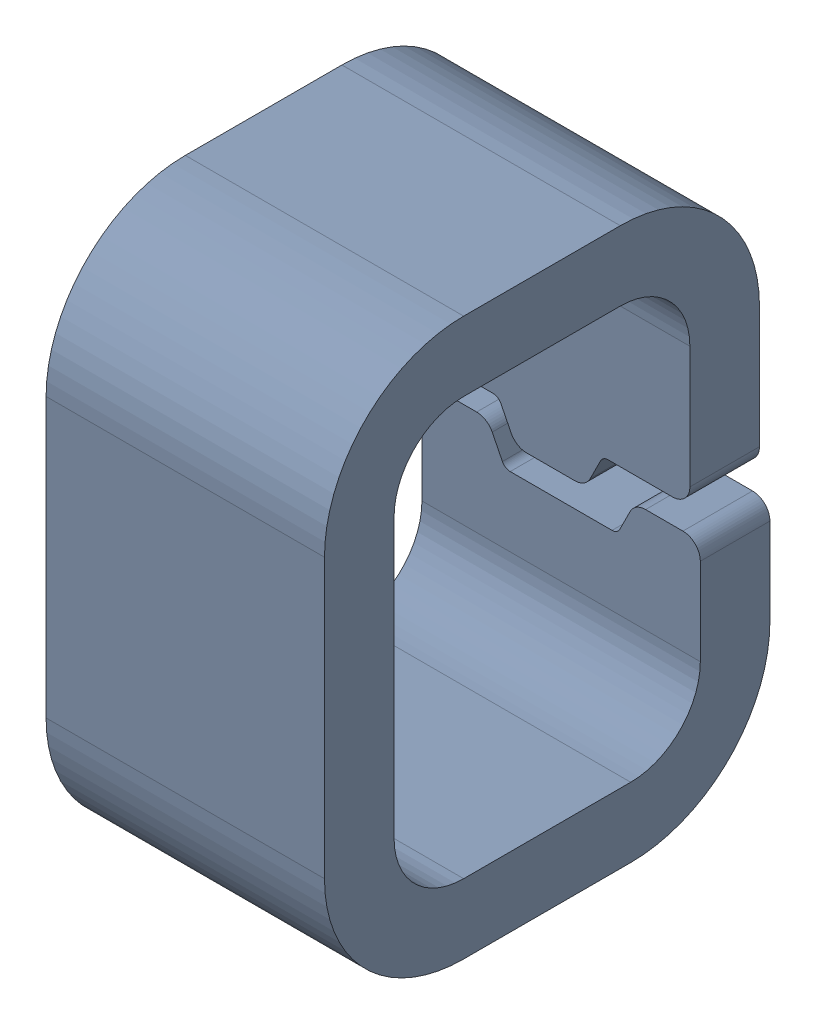
SolidWorks assembly TP1, configuration Default. Lengths in mm.
Overall size (0.8 1.6 1.28).
2 component instances, 1 part files, 0 mates.
Components (placement in the parent):
- Conn_Harwin_S2761-46R_eec-1: Conn_Harwin_S2761-46R_eec [Default] at (37.211 1.651 0) x (0 -1 0) z (0 0 1) size (1.6 0.8 1.28)
  - TP-1: TP [Default] at origin size (1.6 0.8 1.28)
